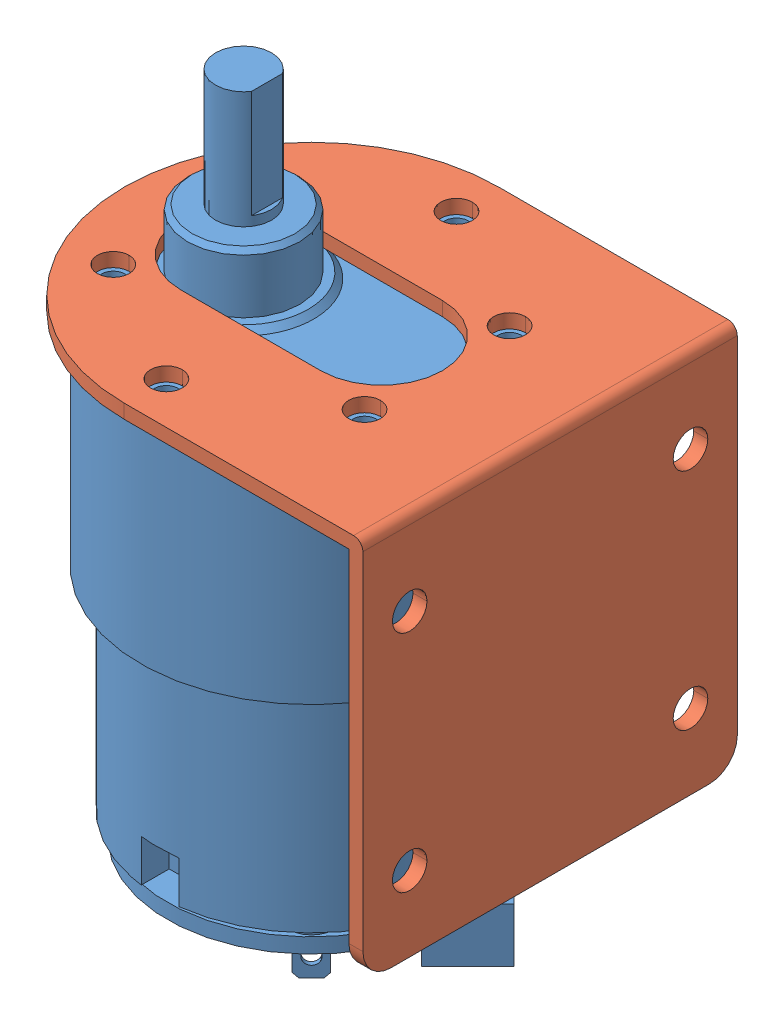
SolidWorks assembly 装配体, configuration 默认. Lengths in mm.
Overall size (45.5 73.2 40).
2 component instances, 2 part files, 3 mates.
Components (placement in the parent):
- 电机-1: 电机 [默认] at origin size (36.5 73.2 36.5)
- 电机支架-1: 电机支架 [默认] at (25.5 1.5 20) x (0 -1 0) z (0 0 -1) size (41 45.5 40)
Mates (geometry in assembly coordinates):
- 重合1: coincident: plane of 电机-1 through (-4.8901 0 0) normal (0 1 0); plane of 电机支架-1 through (24 0 -20) normal (0 -1 0)
- 同心1: concentric: cylinder of 电机-1 through (-13.4234 -8 -7.75) axis (0 1 0) radius 1.25; cylinder of 电机支架-1 through (-13.4234 1.5 -7.75) axis (0 1 0) radius 1.7
- 同心2: concentric aligned: cylinder of 电机-1 through (-13.4234 -8 7.75) axis (0 1 0) radius 1.25; cylinder of 电机支架-1 through (-13.4234 1.5 7.75) axis (0 1 0) radius 1.7
